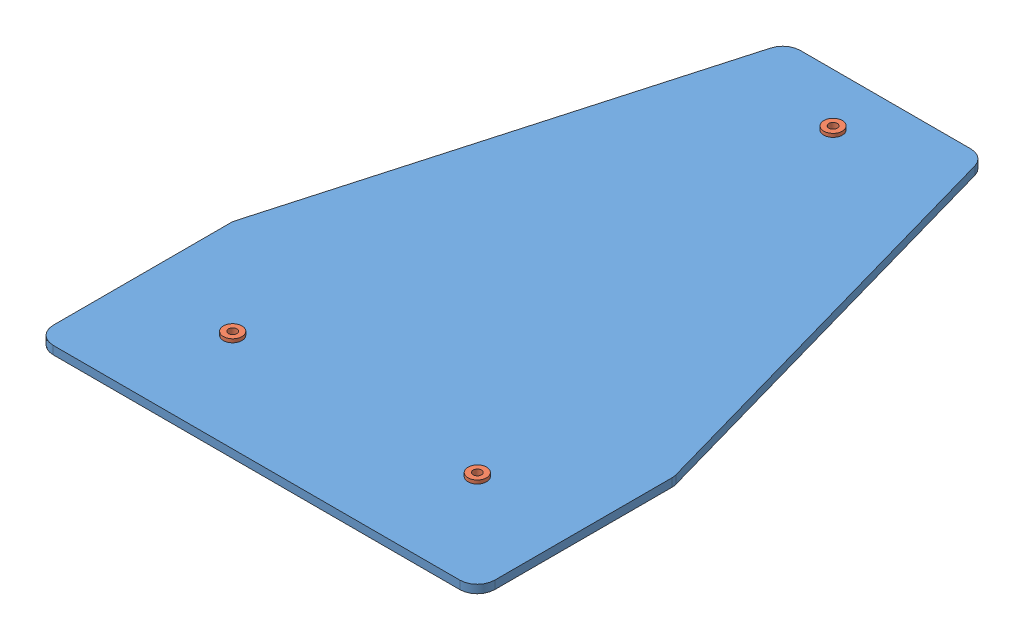
SolidWorks assembly custom_T_w_rivets, configuration Default. Lengths in mm.
Overall size (126.36 7 180).
4 component instances, 2 part files, 6 mates.
Components (placement in the parent):
- custom_T_gusset-1: custom_T_gusset [Default] at (51.9759 0.1551 33.486) size (126.36 2.36 180)
- 0.3125 rivet170927-1: 0.3125 rivet170927 [Default] at (16.9759 2.5151 33.486) size (5.3 7 5.3)
- 0.3125 rivet170927-2: 0.3125 rivet170927 [Default] at (51.9759 2.5151 -103.334) x (0.982082 0 -0.188455) z (0.188455 0 0.982082) size (5.3 7 5.3)
- 0.3125 rivet170927-3: 0.3125 rivet170927 [Default] at (86.9759 2.5151 33.486) x (0.918365 0 -0.395734) z (0.395734 0 0.918365) size (5.3 7 5.3)
Mates (geometry in assembly coordinates):
- Coincident1: coincident anti-aligned: plane of custom_T_gusset-1 through (51.9759 2.5151 33.486) normal (0 1 0); plane of 0.3125 rivet170927-1 through (15.3259 2.5151 33.486) normal (0 -1 0)
- Concentric1: concentric aligned: circle of custom_T_gusset-1; circle of 0.3125 rivet170927-1
- Coincident2: coincident anti-aligned: plane of custom_T_gusset-1 through (51.9759 2.5151 33.486) normal (0 1 0); plane of 0.3125 rivet170927-2 through (50.3555 2.5151 -103.0231) normal (0 -1 0)
- Concentric2: concentric aligned: circle of custom_T_gusset-1; circle of 0.3125 rivet170927-2
- Coincident3: coincident anti-aligned: plane of custom_T_gusset-1 through (51.9759 2.5151 33.486) normal (0 1 0); plane of 0.3125 rivet170927-3 through (85.4606 2.5151 34.1389) normal (0 -1 0)
- Concentric3: concentric aligned: circle of custom_T_gusset-1; circle of 0.3125 rivet170927-3
